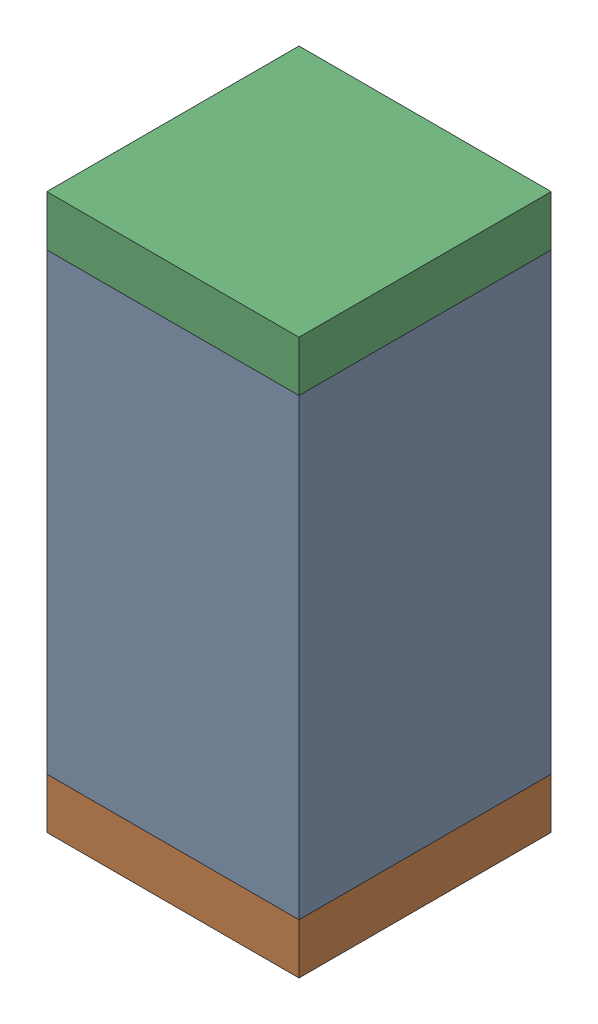
SolidWorks assembly R61, configuration Default. Lengths in mm.
Overall size (0.5 1.1 0.5).
6 component instances, 2 part files, 0 mates.
Components (placement in the parent):
- 791586336-1: 791586336 [Default] at (115 71.15 0) size (0.5 0.9 0.5)
  - Extruded_8-1: Extruded_8 [Default] at origin size (0.5 0.9 0.5)
- 810157360-1: 810157360 [Default] at (115 70.65 0) size (0.5 0.1 0.5)
  - Extruded_9-1: Extruded_9 [Default] at origin size (0.5 0.1 0.5)
- 810157360-2: 810157360 [Default] at (115 71.65 0) size (0.5 0.1 0.5)
  - Extruded_9-1: Extruded_9 [Default] at origin size (0.5 0.1 0.5)
